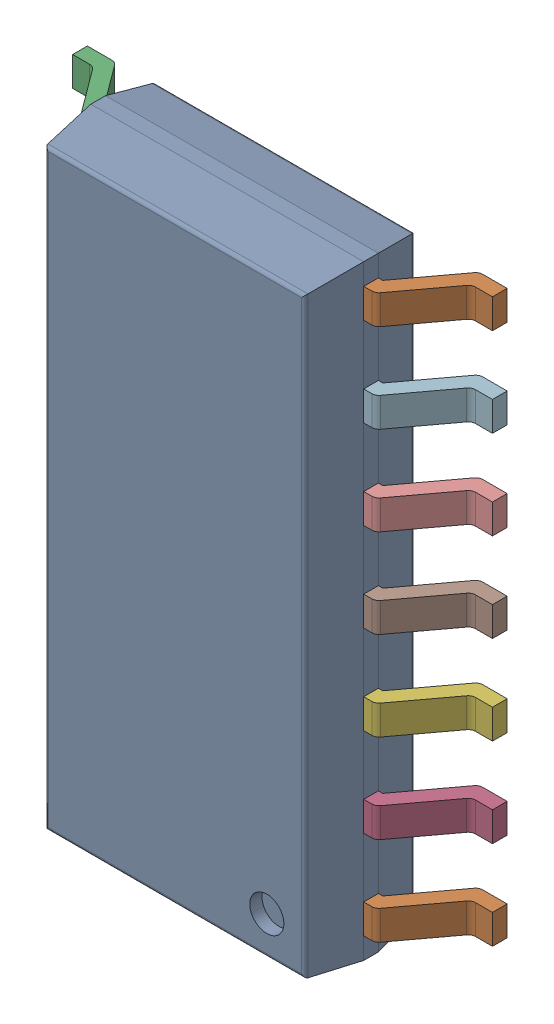
SolidWorks assembly IC11_IC101_1.step, configuration Default. Lengths in mm.
Overall size (6 8.65 1.75).
3 component instances, 2 part files, 0 mates.
Components (placement in the parent):
- 6348793888_1.step-11: 6348793888_1.step [Default] at (487.749 291.435 0) x (-1 0 0) z (0 0 1) size (6 8.65 1.75)
  - Body-16_1.step-54: Body-16_1.step [Default] at origin size (3.9 8.65 1.57)
  - PinsArrayLR-17_1.step-54: PinsArrayLR-17_1.step [Default] at origin size (6 8.04 1)
